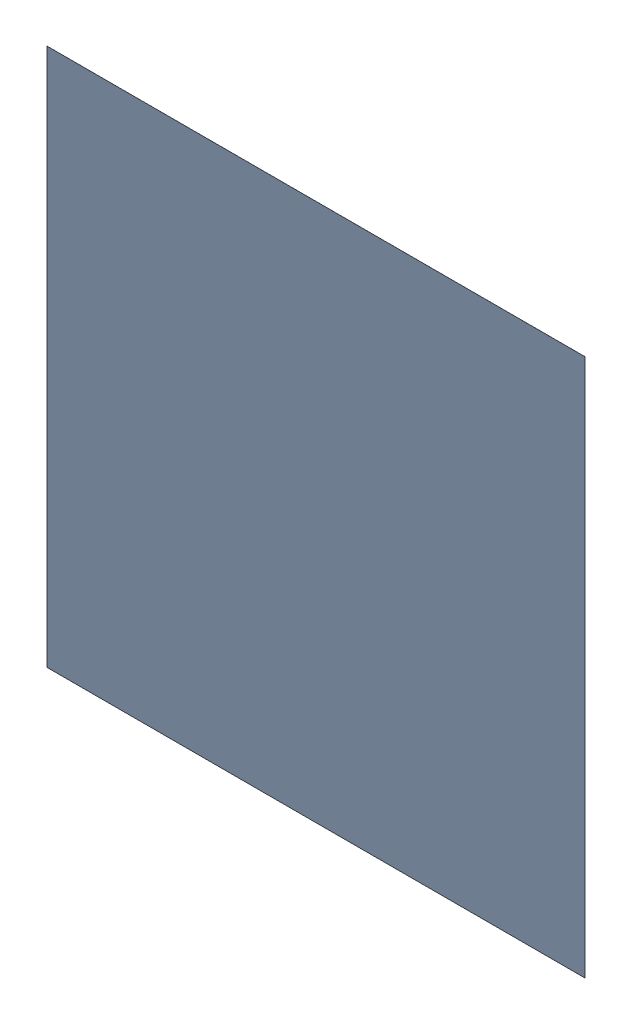
SolidWorks assembly X3, configuration Standard. Lengths in mm.
Overall size (0.05 0.05 0).
2 component instances, 1 part files, 0 mates.
Components (placement in the parent):
- 6269211456-1: 6269211456 [Standard] at (1.3 -23.5 0) x (0 1 0) z (0 0 1) size (0.05 0.05 0)
  - Extruded-3-1: Extruded-3 [Standard] at origin size (0.05 0.05 0)
